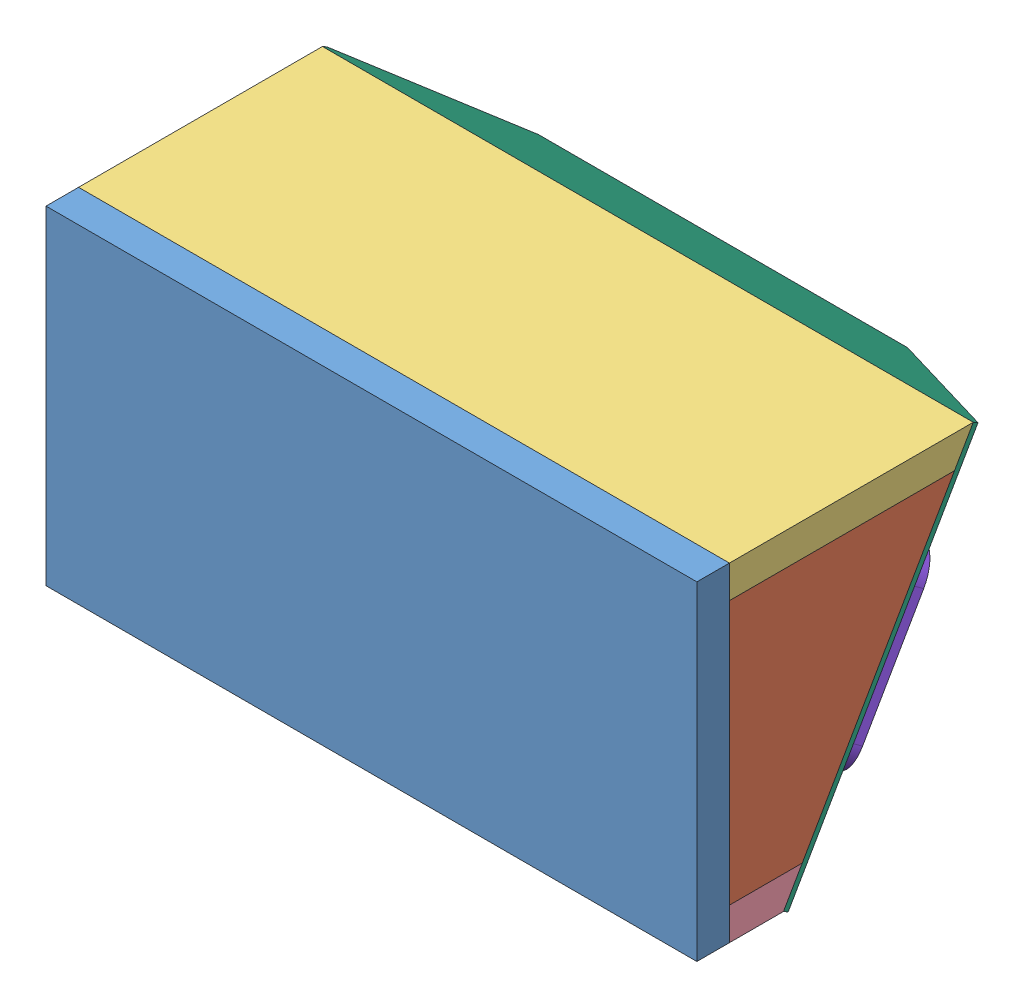
SolidWorks assembly Rigi_Maarten_Enkel_surround, configuration Default. Lengths in mm.
Overall size (240 137.49 131.08).
9 component instances, 8 part files, 20 mates.
Components (placement in the parent):
- Baksida-1: Baksida [Default] at (151.6814 198.2363 222.1405) size (240 121.24 12)
- Sida_Vänster-1: Sida_Vänster [Default] at (151.6814 186.2363 210.1405) size (12 97.24 83)
- Topp-1: Topp [Default] at (151.6814 198.2363 222.1405) size (240 12 89.93)
- Botten-1: Botten [Default] at (151.6814 88.9963 210.1405) size (240 12 26.86)
- Sida_Höger-1: Sida_Höger [Default] at (-76.3186 186.2363 210.1405) size (12 97.24 83)
- Tjock baffel-1: Tjock baffel [Default] at (31.6814 198.2363 120.2123) x (0 0.5 0.866025) z (1 0 0) size (32 140 240)
- SB12PAC25-4-1: SB12PAC25-4 [Default] at (31.6814 121.6145 127.4995) x (-0.999989 -0.004004 0.002312) z (0.004623 -0.866016 0.499995) size (108.9 69.5 108.9)
- BC25SC55-04-1: BC25SC55-04 [Default] at (-62.347 129.1145 140.4899) x (0.001123 0.865701 -0.500561) z (-0.5 -0.433013 -0.75) size (70 54 20.5)
- BC25SC55-04-2: BC25SC55-04 [Default] at (125.7099 129.1145 140.4899) x (-0.000464 -0.866159 0.499768) z (0.5 -0.433013 -0.75) size (70 54 20.5)
Mates (geometry in assembly coordinates):
- Coincident4: coincident: plane of Baksida-1 through (151.6814 198.2363 222.1405) normal (1 0 0); plane of Sida_Vänster-1 through (151.6814 186.2363 210.1405) normal (1 0 0)
- Coincident6: coincident: plane of Sida_Vänster-1 through (139.6814 186.2363 210.1405) normal (0 1 0); plane of Topp-1 through (-88.3186 186.2363 210.1405) normal (0 -1 0)
- Coincident7: coincident: plane of Sida_Vänster-1 through (151.6814 186.2363 210.1405) normal (1 0 0); plane of Topp-1 through (151.6814 198.2363 222.1405) normal (1 0 0)
- Coincident10: coincident: plane of Sida_Vänster-1 through (139.6814 186.2363 210.1405) normal (0 1 0); plane of Topp-1 through (-88.3186 186.2363 210.1405) normal (0 -1 0)
- Coincident12: coincident: plane of Baksida-1 through (-88.3186 198.2363 222.1405) normal (0 1 0); plane of Topp-1 through (-88.3186 198.2363 210.1405) normal (0 1 0)
- Coincident13: coincident: plane of Baksida-1 through (-88.3186 198.2363 210.1405) normal (0 0 -1); plane of Botten-1 through (-88.3186 88.9963 210.1405) normal (0 0 1)
- Coincident14: coincident: plane of Baksida-1 through (151.6814 198.2363 222.1405) normal (1 0 0); plane of Botten-1 through (151.6814 88.9963 210.1405) normal (1 0 0)
- Coincident15: coincident: plane of Baksida-1 through (-88.3186 76.9963 222.1405) normal (0 -1 0); plane of Botten-1 through (-88.3186 76.9963 210.1405) normal (0 -1 0)
- Coincident16: coincident: plane of Sida_Höger-1 through (-88.3186 186.2363 210.1405) normal (0 1 0); plane of Topp-1 through (-88.3186 186.2363 210.1405) normal (0 -1 0)
- Coincident17: coincident: plane of Baksida-1 through (-88.3186 198.2363 210.1405) normal (0 0 -1); plane of Sida_Höger-1 through (-88.3186 88.9963 210.1405) normal (0 0 1)
- Coincident18: coincident: plane of Baksida-1 through (-88.3186 198.2363 222.1405) normal (-1 0 0); plane of Sida_Höger-1 through (-88.3186 186.2363 210.1405) normal (-1 0 0)
- Coincident23: coincident: plane of Sida_Höger-1 through (-88.3186 186.2363 127.1405) normal (0 -0.5 -0.866025); plane of Tjock baffel-1 through (-88.3186 76.9928 190.2123) normal (0 0.5 0.866025)
- Coincident24: coincident: plane of Topp-1 through (-88.3186 198.2363 210.1405) normal (0 1 0); line of Tjock baffel-1 through (151.6814 198.2363 120.2123) axis (-1 0 0)
- Coincident25: coincident: plane of Sida_Höger-1 through (-88.3186 186.2363 210.1405) normal (-1 0 0); plane of Tjock baffel-1 through (-88.3186 76.9928 190.2123) normal (-1 0 0)
- Concentric1: concentric: cylinder of Tjock baffel-1 through (105.7099 146.4351 170.4899) axis (0.5 -0.433013 -0.75) radius 20; cylinder of BC25SC55-04-2 through (117.9599 135.8262 152.1149) axis (0.5 -0.433013 -0.75) radius 14.5748
- Concentric2: concentric: cylinder of Tjock baffel-1 through (-42.347 146.4351 170.4899) axis (-0.5 -0.433013 -0.75) radius 20; cylinder of BC25SC55-04-1 through (-54.597 135.8262 152.1149) axis (-0.5 -0.433013 -0.75) radius 14.5748
- Coincident26: coincident: plane of Tjock baffel-1 through (151.6814 75.9901 188.4756) normal (0.5 -0.433013 -0.75); plane of BC25SC55-04-2 through (140.4428 152.881 136.5902) normal (-0.5 0.433013 0.75)
- Coincident27: coincident: plane of Tjock baffel-1 through (-88.3186 75.9901 188.4756) normal (-0.5 -0.433013 -0.75); plane of BC25SC55-04-1 through (-77.0947 113.8696 159.1234) normal (0.5 0.433013 0.75)
- Concentric3: concentric: cylinder of Tjock baffel-1 through (31.6814 141.6145 162.1405) axis (0 -0.5 -0.866025) radius 51; cylinder of SB12PAC25-4-1 through (31.6814 151.1145 178.595) axis (0 -0.5 -0.866025) radius 40
- Coincident28: coincident: plane of Tjock baffel-1 through (-36.3663 60.9928 162.4995) normal (0 -0.5 -0.866025); plane of SB12PAC25-4-1 through (46.6158 139.2088 117.3414) normal (0 0.5 0.866025)
